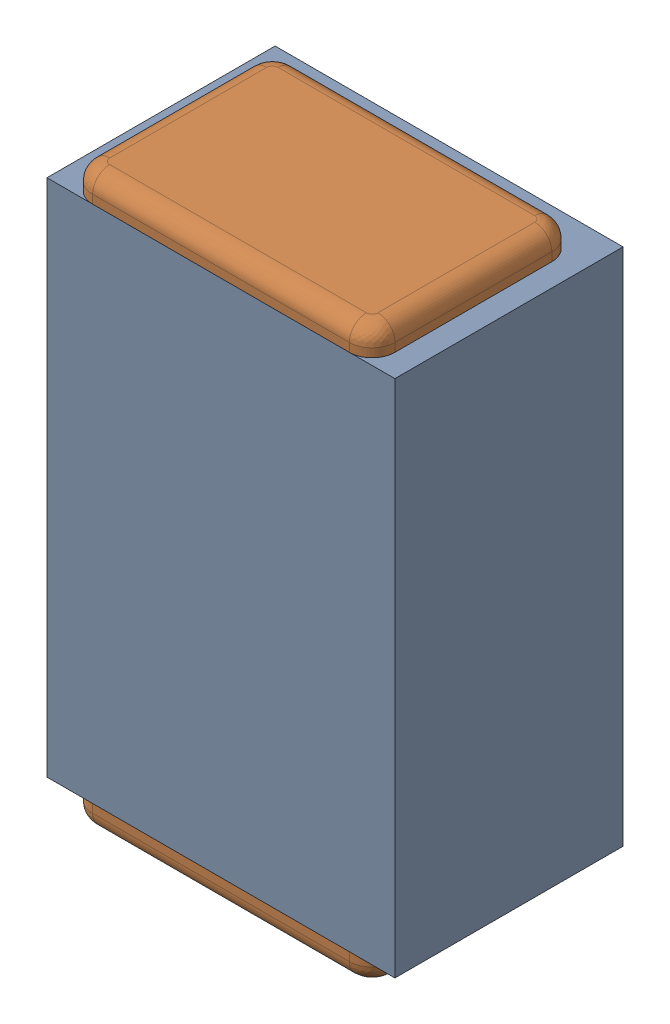
SolidWorks assembly C30, configuration Default. Lengths in mm.
Overall size (0.61 1 0.4).
3 component instances, 2 part files, 0 mates.
Components (placement in the parent):
- 1088881848-1: 1088881848 [Default] at (11.375 31.775 -2.044) size (0.61 0.91 0.4)
  - Extruded-1-1: Extruded-1 [Default] at origin size (0.61 0.91 0.4)
- C0402-1: C0402 [Default] at (11.3751 31.7751 -1.644) x (0 1 0) z (-1 0 0) size (1 0.36 0.54)
